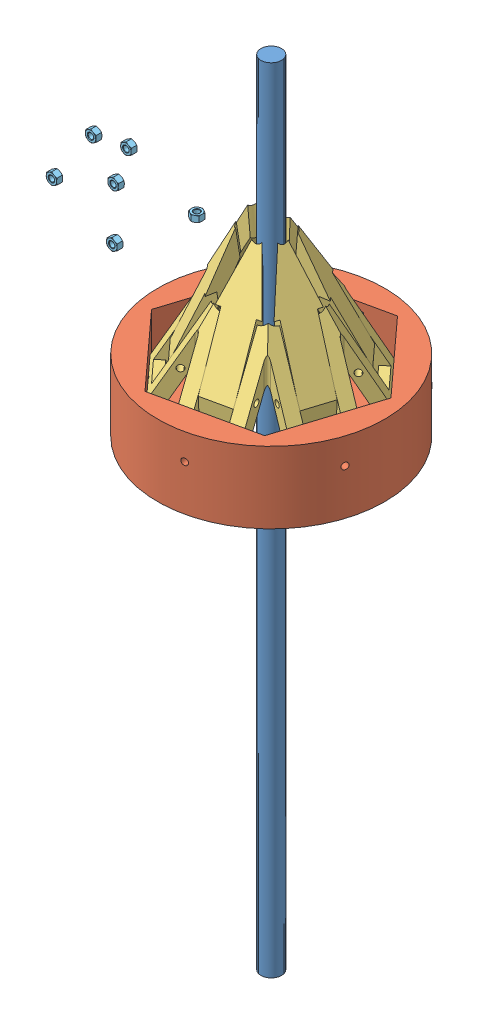
SolidWorks assembly Manipulator, configuration Default. Lengths in mm.
Overall size (207.98 609.6 207.98).
17 component instances, 5 part files, 46 mates.
Components (placement in the parent):
- Rope-1: Rope [Default] at origin size (15.88 609.6 15.88)
- Case-1: Case [Default] at (0 50.4617 0) x (-0.976822 0 0.214052) z (-0.214052 0 -0.976822) size (174.64 55 174.64)
- CASE inside-2: CASE inside [smaller1] at (0 203.354 0) x (0.673785 0 0.738927) z (0.738927 0 -0.673785) size (137.43 83.17 133.92)
- CASE inside-3: CASE inside [inside1] at (-1.9665 198.8869 -8.9739) x (-0.303357 0.050862 0.951519) z (0.952794 0.029365 0.302194) size (47.55 93.48 35.9)
- CASE inside-4: CASE inside [inside1] at (-16.9084 202.1732 -5.3767) x (0.664195 0.131642 0.735877) z (0.73339 0.076003 -0.675546) size (47.55 93.48 35.9)
- CASE inside-6: CASE inside [inside1] at (-11.074 201.2145 10.0977) x (0.972009 0.106023 -0.209662) z (-0.216831 0.061212 -0.974288) size (47.55 93.48 35.9)
- CASE inside-7: CASE inside [inside1] at (2.0646 199.0868 9.4219) x (0.303415 0.055288 -0.951253) z (-0.95276 0.031921 -0.302041) size (47.55 93.48 35.9)
- CASE inside-9: CASE inside [inside1] at (8.4421 198.7421 2.6845) x (-0.672533 0.047688 -0.738529) z (-0.738204 0.027533 0.674015) size (47.55 93.48 35.9)
- CASE inside-10: CASE inside [inside1] at (7.1052 199.0738 -6.4788) x (-0.975531 0.054999 0.212874) z (0.214798 0.031754 0.976142) size (47.55 93.48 35.9)
- socket head cap screw_am-1: socket head cap screw_am [B18.3.1M - 5 x 0.8 x 50 Hex SHCS -- 22CHX] at (-36.2131 109.4162 -41.676) x (0.976822 0 -0.214052) z (0.212843 -0.106112 0.971307) size (55 8.5 8.5)
- hex nut style 1_am-1: hex nut style 1_am [B18.2.4.1M - Hex nut, Style 1,  M5 x 0.8 --D-C] at (10.5825 109.4162 -51.9303) x (0.214052 0 0.976822) z (-0.976822 0 0.214052) size (8 9.24 4.7)
- hex nut style 1_am-2: hex nut style 1_am [B18.2.4.1M - Hex nut, Style 1,  M5 x 0.8 --D-C] at (-44.161 184.7927 13.0846) x (1 0 0) z (0 1 0) size (8 9.24 4.7)
- hex nut style 1_am-3: hex nut style 1_am [B18.2.4.1M - Hex nut, Style 1,  M5 x 0.8 --D-C] at (-49.068 190.3931 73.6434) size (8 9.24 4.7)
- hex nut style 1_am-4: hex nut style 1_am [B18.2.4.1M - Hex nut, Style 1,  M5 x 0.8 --D-C] at (-56.8603 240.872 54.9686) size (8 9.24 4.7)
- hex nut style 1_am-5: hex nut style 1_am [B18.2.4.1M - Hex nut, Style 1,  M5 x 0.8 --D-C] at (-78.979 227.4603 90.088) size (8 9.24 4.7)
- hex nut style 1_am-6: hex nut style 1_am [B18.2.4.1M - Hex nut, Style 1,  M5 x 0.8 --D-C] at (-56.6556 222.5062 65.0425) size (8 9.24 4.7)
- hex nut style 1_am-7: hex nut style 1_am [B18.2.4.1M - Hex nut, Style 1,  M5 x 0.8 --D-C] at (-70.9408 248.8606 68.0306) size (8 9.24 4.7)
Mates (geometry in assembly coordinates):
- Coincident30: coordinate: point of assembly; point of Rope-1; point of assembly
- Concentric3: concentric aligned: cylinder of Rope-1 through (0 304.8 0) axis (0 -1 0) radius 7.9375; cylinder of Case-1 through (0 65.4617 0) axis (0 -1 0) radius 39.6875
- Concentric6: concentric aligned: cylinder of hex clip piece-13 through (0 32.5714 0) axis (0 -1 0) radius 6.35; cylinder of Rope-1 through (0 304.8 0) axis (0 -1 0) radius 7.9375
- Concentric7: concentric aligned: cylinder of hex clip piece-7 through (0 33.7354 0) axis (0 -1 0) radius 6.35; cylinder of Rope-1 through (0 304.8 0) axis (0 -1 0) radius 7.9375
- Coincident31: coincident anti-aligned: plane of case1 - Copy-1 through (0 308.2534 0) normal (-0.999808 0 -0.019586); plane of case1 - Copy-2 through (0 308.2534 0) normal (0.999808 0 0.019586)
- Concentric8: concentric aligned: cylinder of case1 - Copy-1 through (0 308.2534 0) axis (0 -1 0) radius 6.35; cylinder of case1 - Copy-2 through (0 308.2534 0) axis (0 -1 0) radius 6.35
- Coincident33: coincident aligned: line of case1 - Copy-1 through (-1.0401 114.3867 53.0958) axis (0.014805 -0.654654 -0.755784); line of case1 - Copy-2 through (-1.0401 114.3867 53.0958) axis (0.014805 -0.654654 -0.755784)
- Coincident36: coincident aligned: line of case1 - Copy-2 through (-46.5024 114.3867 25.6471) axis (0.661931 -0.654654 -0.36507); line of case1 - Copy-3 through (-46.5024 114.3867 25.6471) axis (0.661931 -0.654654 -0.36507)
- Coincident37: coincident anti-aligned: plane of case1 - Copy-2 through (0 308.2534 0) normal (-0.482943 0 -0.875652); plane of case1 - Copy-3 through (0 308.2534 0) normal (0.482943 0 0.875652)
- Concentric10: concentric aligned: cylinder of case1 - Copy-2 through (0 308.2534 0) axis (0 -1 0) radius 6.35; cylinder of case1 - Copy-3 through (0 308.2534 0) axis (0 -1 0) radius 6.35
- Concentric11: concentric aligned: cylinder of Rope-1 through (0 304.8 0) axis (0 -1 0) radius 7.9375; cylinder of case1 - Copy-2 through (0 308.2534 0) axis (0 -1 0) radius 6.35
- Coincident38: coincident anti-aligned: plane of case1 - Copy-1 through (0 308.2534 0) normal (0.516866 0 -0.856067); plane of case1 - Copy-4 through (0 308.2534 0) normal (-0.516866 0 0.856067)
- Coincident39: coincident aligned: line of case1 - Copy-1 through (45.4623 114.3867 27.4487) axis (-0.647125 -0.654654 -0.390714); line of case1 - Copy-4 through (45.4623 114.3867 27.4487) axis (-0.647125 -0.654654 -0.390714)
- Concentric12: concentric aligned: cylinder of case1 - Copy-1 through (0 308.2534 0) axis (0 -1 0) radius 6.35; cylinder of case1 - Copy-4 through (0 308.2534 0) axis (0 -1 0) radius 6.35
- Coincident40: coincident aligned: line of case1 - Copy-4 through (46.5024 114.3867 -25.6471) axis (-0.661931 -0.654654 0.36507); line of case1 - Copy-5 through (46.5024 114.3867 -25.6471) axis (-0.661931 -0.654654 0.36507)
- Coincident41: coincident anti-aligned: plane of case1 - Copy-4 through (0 308.2534 0) normal (-0.482943 0 -0.875652); plane of case1 - Copy-5 through (0 308.2534 0) normal (0.482943 0 0.875652)
- Concentric13: concentric aligned: cylinder of case1 - Copy-4 through (0 308.2534 0) axis (0 -1 0) radius 6.35; cylinder of case1 - Copy-5 through (0 308.2534 0) axis (0 -1 0) radius 6.35
- Coincident42: coincident aligned: line of case1 - Copy-5 through (1.0401 114.3867 -53.0958) axis (-0.014805 -0.654654 0.755784); line of case1 - Copy-6 through (1.0401 114.3867 -53.0958) axis (-0.014805 -0.654654 0.755784)
- Coincident43: coincident anti-aligned: plane of case1 - Copy-5 through (0 308.2534 0) normal (-0.999808 0 -0.019586); plane of case1 - Copy-6 through (0 308.2534 0) normal (0.999808 0 0.019586)
- Concentric15: concentric aligned: cylinder of case1 - Copy-5 through (0 308.2534 0) axis (0 -1 0) radius 6.35; cylinder of case1 - Copy-6 through (0 308.2534 0) axis (0 -1 0) radius 6.35
- Coincident47: coincident anti-aligned: plane of Case-1 through (-49.48 183.4736 45.118) normal (0.738927 0 -0.673785); plane of case1 - Copy - Copy-1 through (-83.412 -86.1077 -16.2015) normal (-0.878007 0 -0.478649)
- Concentric16: concentric aligned: cylinder of Case-1 through (-83.2151 85.4617 -26.4615) axis (0.952979 0 0.303037) radius 2.5; cylinder of CASE inside-1 through (-2.1142 35 -86.3346) axis (0.024481 0 0.9997) radius 2.5
- Coincident49: coincident: plane of CASE inside-1 through (0 118.6333 0) normal (-0.021201 0.5 -0.865766); plane of copy-1 through (-0.054 116.4277 -2.2049) normal (-0.017311 0.707107 -0.706895)
- Parallel2: parallel: plane of CASE inside-1 through (-36.6205 -135.3667 -65.7449) normal (0.024481 0 0.9997); plane of copy-1 through (-39.7581 -137.5723 -67.2435) normal (-0.024481 0 -0.9997)
- Coincident51: coincident anti-aligned: plane of CASE inside-1; plane of copy-1 through (-19.7641 36.2944 -67.7331) normal (-0.9997 0 0.024481)
- Width1: width anti-aligned: plane of CASE inside-2 through (-22.31 93.354 -48.3056) normal (0.976822 0 -0.214052); plane of CASE inside-3 through (0.0651 93.354 -53.2087) normal (-0.976822 0 0.214052); plane of CASE inside-2 through (-22.8744 86.025 -50.8814) normal (-0.976822 0 0.214052); plane of CASE inside-3 through (-0.4993 86.025 -55.7844) normal (0.976822 0 -0.214052)
- Concentric18: concentric anti-aligned: cylinder of CASE inside-2 through (17.4897 109.4162 -53.4439) axis (-0.976822 0 0.214052) radius 2.5; cylinder of CASE inside-3 through (-39.1931 109.4162 -41.023) axis (0.976822 0 -0.214052) radius 2.5
- Concentric23: concentric aligned: cylinder of Case-1 through (83.2151 85.4617 26.4615) axis (-0.952979 0 -0.303037) radius 2.5; cylinder of CASE inside-2 through (63.8129 85.4617 20.2918) axis (-0.952979 0 -0.303037) radius 2.5
- Coincident54: coincident anti-aligned: plane of Case-1 through (63.8133 183.4736 20.2919) normal (-0.952979 0 -0.303037); plane of CASE inside-2 through (72.904 -50.646 -8.2976) normal (0.952979 0 0.303037)
- Concentric27: concentric aligned: cylinder of Case-1 through (-64.5239 85.4617 58.8356) axis (0.738927 0 -0.673785) radius 2.5; cylinder of CASE inside-2 through (-49.4797 85.4617 45.1177) axis (0.738927 0 -0.673785) radius 2.5
- Coincident55: coincident anti-aligned: plane of CASE inside-2 through (-52.9889 93.354 -4.8318) normal (0.303037 0 -0.952979); plane of CASE inside-4 through (-53.3874 85.553 -4.9585) normal (-0.303037 0 0.952979)
- Concentric28: concentric anti-aligned: cylinder of CASE inside-2 through (-37.539 109.4162 -41.8685) axis (-0.303037 0 0.952979) radius 2.5; cylinder of CASE inside-4 through (-55.1235 109.4162 13.4307) axis (0.303037 0 -0.952979) radius 2.5
- Coincident59: coincident anti-aligned: plane of CASE inside-2 through (-30.6789 93.354 43.4738) normal (-0.673785 0 -0.738927); plane of CASE inside-6 through (-31.5132 85.6806 44.2346) normal (0.673785 0 0.738927)
- Concentric30: concentric anti-aligned: cylinder of CASE inside-2 through (-55.0286 109.4162 11.5755) axis (0.673785 0 0.738927) radius 2.5; cylinder of CASE inside-6 through (-15.9304 109.4162 54.4537) axis (-0.673785 0 -0.738927) radius 2.5
- Coincident60: coincident anti-aligned: plane of CASE inside-2 through (22.31 93.354 48.3056) normal (-0.976822 0 0.214052); plane of CASE inside-7 through (22.8488 85.9939 50.7643) normal (0.976822 0 -0.214052)
- Concentric31: concentric anti-aligned: cylinder of CASE inside-2 through (-17.4897 109.4162 53.4439) axis (0.976822 0 -0.214052) radius 2.5; cylinder of CASE inside-7 through (39.1931 109.4162 41.023) axis (-0.976822 0 0.214052) radius 2.5
- Coincident61: coincident anti-aligned: plane of CASE inside-2 through (52.9889 93.354 4.8318) normal (-0.303037 0 0.952979); plane of CASE inside-9 through (55.5835 86.0477 5.6569) normal (0.303037 0 -0.952979)
- Concentric32: concentric anti-aligned: cylinder of CASE inside-2 through (37.539 109.4162 41.8685) axis (0.303037 0 -0.952979) radius 2.5; cylinder of CASE inside-9 through (55.1235 109.4162 -13.4307) axis (-0.303037 0 0.952979) radius 2.5
- Coincident62: coincident anti-aligned: plane of CASE inside-2 through (30.6789 93.354 -43.4738) normal (0.673785 0 0.738927); plane of CASE inside-10 through (32.5446 85.9959 -45.175) normal (-0.673785 0 -0.738927)
- Concentric34: concentric anti-aligned: cylinder of CASE inside-2 through (55.0286 109.4162 -11.5755) axis (-0.673785 0 -0.738927) radius 2.5; cylinder of CASE inside-10 through (15.9304 109.4162 -54.4537) axis (0.673785 0 0.738927) radius 2.5
- Coincident63: coincident anti-aligned: plane of CASE inside-2 through (32.0782 93.354 46.1651) normal (0.976822 0 -0.214052); plane of socket button head cap screw_am-5 through (30.9637 111.2432 41.0793) normal (-0.976822 0 0.214052)
- Concentric35: concentric aligned: cylinder of CASE inside-2 through (-17.4897 109.4162 53.4439) axis (0.976822 0 -0.214052) radius 2.5; cylinder of socket button head cap screw_am-5 through (34.0153 109.4162 42.1576) axis (0.976822 0 -0.214052) radius 2.5
- Coincident64: coincident anti-aligned: plane of CASE inside-2 through (-32.0782 93.354 -46.1651) normal (-0.976822 0 0.214052); plane of socket head cap screw_am-1 through (-31.2325 113.6422 -42.3057) normal (0.976822 0 -0.214052)
- Concentric36: concentric aligned: cylinder of CASE inside-2 through (17.4897 109.4162 -53.4439) axis (-0.976822 0 0.214052) radius 2.5; cylinder of socket head cap screw_am-1 through (-67.2273 109.4162 -34.8798) axis (-0.976822 0 0.214052) radius 2.5
- Coincident65: coincident anti-aligned: plane of CASE inside-2 through (9.8333 93.354 -55.3492) normal (0.976822 0 -0.214052); plane of hex nut style 1_am-1 through (8.8701 109.4162 -59.7449) normal (-0.976822 0 0.214052)
- Concentric37: concentric aligned: cylinder of socket head cap screw_am-1 through (-67.2273 109.4162 -34.8798) axis (-0.976822 0 0.214052) radius 2.5; cylinder of hex nut style 1_am-1 through (15.1736 109.4162 -52.9364) axis (-0.976822 0 0.214052) radius 2.1
